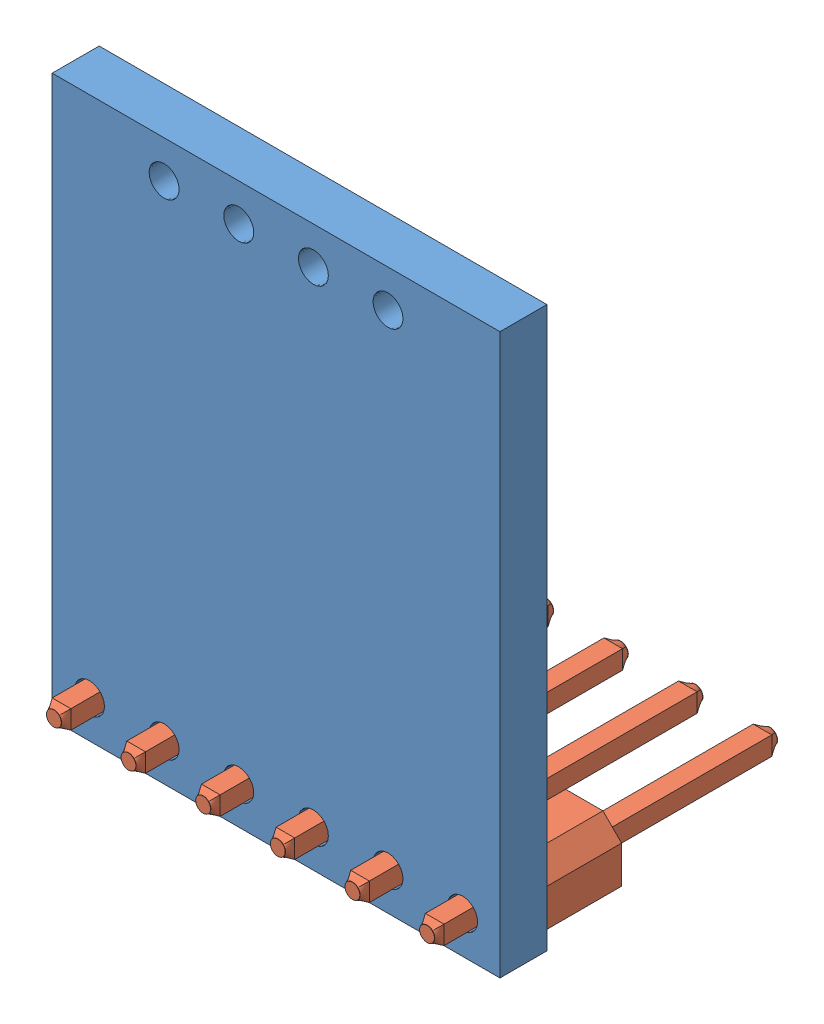
SolidWorks assembly SparkFun OpenLog DEV-09530, configuration Default. Lengths in mm.
Overall size (15.24 19.05 11.76).
8 component instances, 2 part files, 3 mates.
Components (placement in the parent):
- openlog-1: openlog [Default] at origin size (15.24 19.05 1.6)
- Male Header 6 Pin-1: Male Header 6 Pin [Default] at (-5.1542 -49.808 -25.6151) x (0 -1 0) z (0 0 1) size (2.54 15.24 11.76)
  - Male Header Pin-1: Male Header Pin [Default] at (-51.078 6.4242 23.0751) size (2.54 2.54 11.76)
  - Male Header Pin-2: Male Header Pin [Default] at (-51.078 8.9642 23.0751) size (2.54 2.54 11.76)
  - Male Header Pin-3: Male Header Pin [Default] at (-51.078 11.5042 23.0751) size (2.54 2.54 11.76)
  - Male Header Pin-4: Male Header Pin [Default] at (-51.078 14.0442 23.0751) size (2.54 2.54 11.76)
  - Male Header Pin-5: Male Header Pin [Default] at (-51.078 16.5842 23.0751) size (2.54 2.54 11.76)
  - Male Header Pin-6: Male Header Pin [Default] at (-51.078 19.1242 23.0751) size (2.54 2.54 11.76)
Mates (geometry in assembly coordinates):
- Coincident1: coincident: plane of openlog-1 through (15.24 0 0) normal (0 0 -1); plane of Male Header 6 Pin-1/Male Header Pin-6 through (15.24 0 0) normal (0 0 1)
- Concentric1: concentric: cylinder of openlog-1 through (13.97 1.27 1.6) axis (0 0 -1) radius 0.51; cylinder of Male Header 6 Pin-1/Male Header Pin-6 through (13.97 1.27 2.812) axis (0 0 -1) radius 0.254
- Concentric2: concentric aligned: cylinder of openlog-1 through (1.27 1.27 1.6) axis (0 0 -1) radius 0.51; cylinder of Male Header 6 Pin-1/Male Header Pin-1 through (1.27 1.27 2.812) axis (0 0 -1) radius 0.254
